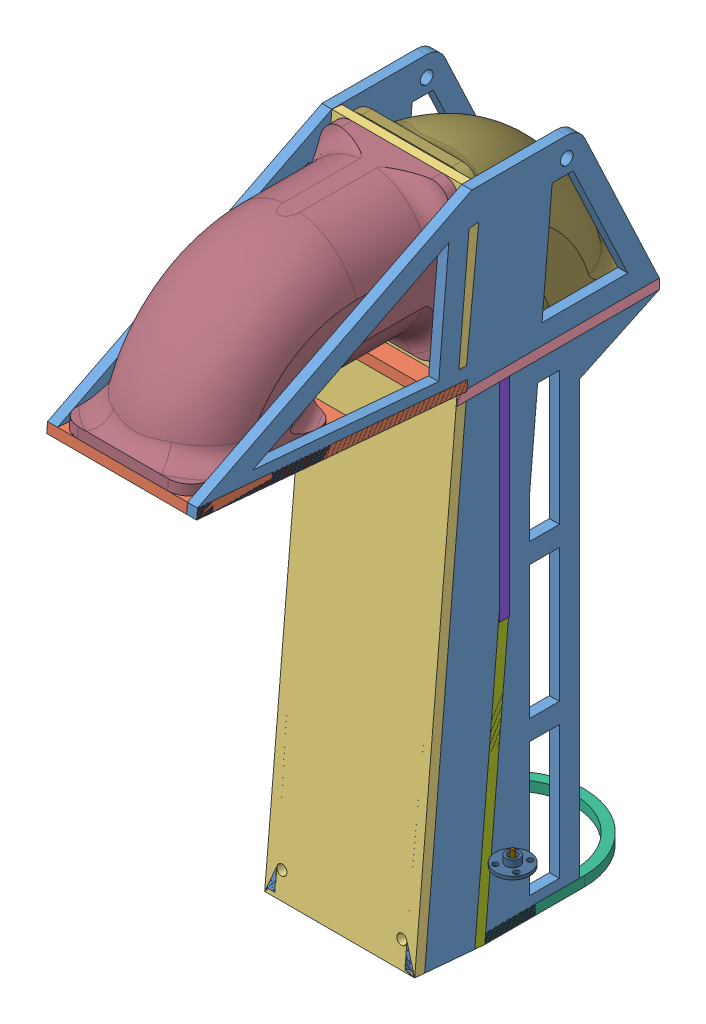
SolidWorks assembly Lift v2B, configuration Default. Lengths in mm.
Overall size (147.55 421.28 293.84).
18 component instances, 13 part files, 33 mates.
Components (placement in the parent):
- Dispenser Side-1: Dispenser Side [Default] at (107.1799 92.3522 433.5335) size (6.35 419.1 293.84)
- Dispenser Side-2: Dispenser Side [Default] at (196.0799 92.3522 433.5335) size (6.35 419.1 293.84)
- Dispenser Front Top-1: Dispenser Front Top [Default] at (107.1799 92.3522 433.5335) x (0 0 -1) z (1 0 0) size (172.16 21.34 95.25)
- Dispenser Front-1: Dispenser Front [Default] at (202.4299 91.7988 427.2076) x (0 0.173648 0.984808) z (-1 0 0) size (42.65 415.78 95.25)
- Dispenser Back Top-2: Dispenser Back Top [Default] at (107.1799 92.3522 433.5335) x (0 0 -1) z (1 0 0) size (128.5 6.35 95.25)
- Tetrix Worm Channel 64mm-1: Tetrix Worm Channel 64mm [Default] at (156.7805 161.35 405.0616) x (0 0.087156 0.996195) z (-1 0 0) size (32 32 64)
- Dispenser Bottom-1: Dispenser Bottom [Default] at (107.1799 92.3522 433.5335) x (0 0 -1) z (1 0 0) size (111.1 6.35 95.25)
- Dispenser Inside Bottom-1: Dispenser Inside Bottom [Default] at (107.1799 92.3522 433.5335) x (0 0 -1) z (1 0 0) size (21.93 178.91 95.25)
- Dispenser Inside-2: Dispenser Inside [Default] at (107.1799 92.3522 433.5335) x (0 0 -1) z (1 0 0) size (6.35 138.64 95.25)
- Tetrix Servo 180° (with Horn)-1: Tetrix Servo 180° (with Horn) [Default] at (258.2205 184.0789 414.3045) x (-0.837169 0 -0.546944) z (-0.546944 0 0.837169) size (22 10.95 22)
  - Tetrix Servo Body Screw B-1: Tetrix Servo Body Screw B [Default] at (19.125 20.2268 4.9509) size (5.08 10.95 5.08)
  - Tetrix Servo Horn B-1: Tetrix Servo Horn B [Default] at (19.125 18.2268 4.9509) size (22 6.2 22)
- Tetrix Servo 180° (with Horn)-2: Tetrix Servo 180° (with Horn) [Default] at (171.6708 354.963 389.9198) x (0 -1 0) z (0 0 1) size (22 10.95 22)
  - Tetrix Servo Body Screw B-1: Tetrix Servo Body Screw B [Default] at (19.125 20.2268 4.9509) size (5.08 10.95 5.08)
  - Tetrix Servo Horn B-1: Tetrix Servo Horn B [Default] at (19.125 18.2268 4.9509) size (22 6.2 22)
- Back Tube Top Plate-1: Back Tube Top Plate [Default] at (154.8049 397.1522 325.4359) x (-1 0 0) z (0 0 1) size (82.55 6.35 95.25)
- UTurn Tube Back-1: UTurn Tube Back [Default] at (154.8049 92.3522 433.5335) x (0 0 -1) z (1 0 0) size (121.27 110.11 91.11)
- UTurn Tube Front-1: UTurn Tube Front [Default] at (154.8049 92.3522 433.5335) x (0 0 -1) z (1 0 0) size (174.23 97.61 85.54)
Mates (geometry in assembly coordinates):
- Coincident4: coincident aligned: plane of Dispenser Side-1 through (113.5299 96.2263 433.1945) normal (0 -0.996195 0.087156); plane of Dispenser Side-2 through (202.4299 96.2263 433.1945) normal (0 -0.996195 0.087156)
- Coincident5: coincident: line of Dispenser Side-1 through (107.1799 402.8632 406.3673) axis (0 -0.996195 0.087156); plane of Dispenser Side-2 through (202.4299 402.8632 406.3673) normal (0 0.087156 0.996195)
- Coincident11: coincident aligned: plane of Dispenser Side-2 through (202.4299 92.3522 433.5335) normal (1 0 0); plane of Dispenser Front Top-1 through (202.4299 92.3522 433.5335) normal (1 0 0)
- Coincident12: coincident aligned: plane of Dispenser Side-2 through (202.4299 417.3237 571.6507) normal (0 0.087156 0.996195); plane of Dispenser Front Top-1 through (202.4299 423.6495 571.0972) normal (0 0.087156 0.996195)
- Coincident13: coincident aligned: plane of Dispenser Side-2 through (202.4299 417.3237 571.6507) normal (0 -0.996195 0.087156); plane of Dispenser Front Top-1 through (202.4299 417.3237 571.6507) normal (0 -0.996195 0.087156)
- Coincident14: coincident aligned: plane of Dispenser Side-2 through (202.4299 402.8632 406.3673) normal (0 0.087156 0.996195); plane of Dispenser Front-1 through (107.1799 96.2263 433.1945) normal (0 0.087156 0.996195)
- Coincident15: coincident aligned: plane of Dispenser Side-2 through (202.4299 96.2263 433.1945) normal (0 -0.996195 0.087156); plane of Dispenser Front-1 through (107.1799 96.2263 433.1945) normal (0 -0.996195 0.087156)
- Coincident16: coincident aligned: plane of Dispenser Side-2 through (202.4299 92.3522 433.5335) normal (1 0 0); plane of Dispenser Front-1 through (202.4299 91.7988 427.2076) normal (1 0 0)
- Coincident18: coincident aligned: plane of Dispenser Side-1 through (107.1799 92.3522 433.5335) normal (-1 0 0); plane of Dispenser Back Top-2 through (107.1799 92.3522 433.5335) normal (-1 0 0)
- Coincident19: coincident aligned: plane of Dispenser Side-1 through (113.5299 403.5022 277.8109) normal (0 0 -1); plane of Dispenser Back Top-2 through (202.4299 397.1522 277.8109) normal (0 0 -1)
- Coincident20: coincident: line of Dispenser Side-1 through (113.5299 397.1522 277.8109) axis (-1 0 0); plane of Dispenser Back Top-2 through (202.4299 397.1522 277.8109) normal (0 -1 0)
- Coincident21: coincident anti-aligned: plane of Dispenser Front-1 through (107.1799 95.6729 426.8687) normal (0 -0.087156 -0.996195); plane of Tetrix Worm Channel 64mm-1 through (124.7805 176.1931 419.8241) normal (0 0.087156 0.996195)
- Parallel1: parallel anti-aligned: plane of Dispenser Side-2 through (196.0799 92.3522 433.5335) normal (-1 0 0); plane of Tetrix Worm Channel 64mm-1 through (188.7805 146.7247 392.7896) normal (1 0 0)
- Coincident23: coincident aligned: plane of Dispenser Side-1 through (113.5299 92.3522 388.9137) normal (0 -1 0); plane of Dispenser Bottom-1 through (202.4299 92.3522 277.8109) normal (0 -1 0)
- Coincident24: coincident aligned: plane of Dispenser Side-2 through (202.4299 92.3522 433.5335) normal (1 0 0); plane of Dispenser Bottom-1 through (202.4299 92.3522 433.5335) normal (1 0 0)
- Coincident25: coincident: plane of Dispenser Side-1 through (113.5299 373.2464 328.6109) normal (0 0 -1); line of Dispenser Bottom-1 through (107.1799 373.2464 328.6109) axis (0 -1 0)
- Coincident26: coincident aligned: plane of Dispenser Side-2 through (202.4299 92.3522 433.5335) normal (1 0 0); plane of Dispenser Inside Bottom-1 through (202.4299 92.3522 433.5335) normal (1 0 0)
- Coincident27: coincident aligned: plane of Dispenser Side-2 through (202.4299 96.2263 433.1945) normal (0 -0.996195 0.087156); plane of Dispenser Inside Bottom-1 through (202.4299 92.8839 394.9905) normal (0 -0.996195 0.087156)
- Distance2: distance = 32 mm anti-aligned: plane of Dispenser Inside Bottom-1 through (202.4299 92.8839 394.9905) normal (0 0.087156 0.996195); plane of Dispenser Front-1 through (107.1799 95.6729 426.8687) normal (0 -0.087156 -0.996195)
- Coincident29: coincident aligned: plane of Dispenser Side-1 through (107.1799 92.3522 433.5335) normal (-1 0 0); plane of Dispenser Inside-2 through (107.1799 92.3522 433.5335) normal (-1 0 0)
- Coincident30: coincident: line of Dispenser Side-2 through (196.0799 -907.6478 373.0609) axis (0 1 0); plane of Dispenser Inside-2 through (202.4299 403.5022 373.0609) normal (0 0 -1)
- Coincident31: coincident aligned: plane of Dispenser Back Top-2 through (202.4299 403.5022 277.8109) normal (0 1 0); plane of Dispenser Inside-2 through (202.4299 403.5022 373.0609) normal (0 1 0)
- Parallel2: parallel aligned: plane of Dispenser Bottom-1 through (202.4299 98.7022 277.8109) normal (0 1 0); plane of ? through (238.7895 230.2815 426.5784) normal (0 1 0)
- Parallel3: parallel anti-aligned: plane of Dispenser Side-1 through (113.5299 92.3522 433.5335) normal (1 0 0); plane of ? through (172.3977 327.963 359.7708) normal (-1 0 0)
- Coincident35: coincident anti-aligned: plane of Dispenser Back Top-2 through (202.4299 397.1522 277.8109) normal (0 -1 0); plane of Back Tube Top Plate-1 through (154.8049 397.1522 325.4359) normal (0 1 0)
- Coincident36: coincident aligned: plane of Dispenser Back Top-2 through (202.4299 397.1522 277.8109) normal (0 0 -1); plane of Back Tube Top Plate-1 through (113.5299 390.8022 277.8109) normal (0 0 -1)
- Coincident37: coincident anti-aligned: plane of Dispenser Side-1 through (113.5299 92.3522 433.5335) normal (1 0 0); plane of Back Tube Top Plate-1 through (113.5299 390.8022 373.0609) normal (-1 0 0)
- Coincident38: coincident anti-aligned: plane of Dispenser Front-1 through (107.1799 95.6729 426.8687) normal (0 -0.087156 -0.996195); plane of UTurn Tube Back-1 through (111.6249 384.9652 401.5589) normal (0 0.087156 0.996195)
- Coincident40: coincident anti-aligned: plane of Dispenser Side-1 through (113.5299 92.3522 433.5335) normal (1 0 0); plane of UTurn Tube Back-1 through (113.5299 409.8522 277.8109) normal (-1 0 0)
- Coincident41: coincident anti-aligned: plane of Dispenser Back Top-2 through (202.4299 403.5022 277.8109) normal (0 1 0); plane of UTurn Tube Back-1 through (111.6249 403.5022 373.0609) normal (0 -1 0)
- Coincident42: coincident anti-aligned: plane of Dispenser Front Top-1 through (202.4299 423.6495 571.0972) normal (0 0.996195 -0.087156); plane of UTurn Tube Front-1 through (110.3549 415.3479 476.2097) normal (0 -0.996195 0.087156)
- Coincident43: coincident anti-aligned: plane of Dispenser Front-1 through (107.1799 96.2263 433.1945) normal (0 0.087156 0.996195); plane of UTurn Tube Front-1 through (154.8049 92.3522 433.5335) normal (0 -0.087156 -0.996195)
- Coincident44: coincident anti-aligned: plane of Dispenser Side-2 through (196.0799 92.3522 433.5335) normal (-1 0 0); plane of UTurn Tube Front-1 through (196.0799 413.8448 277.4279) normal (1 0 0)
